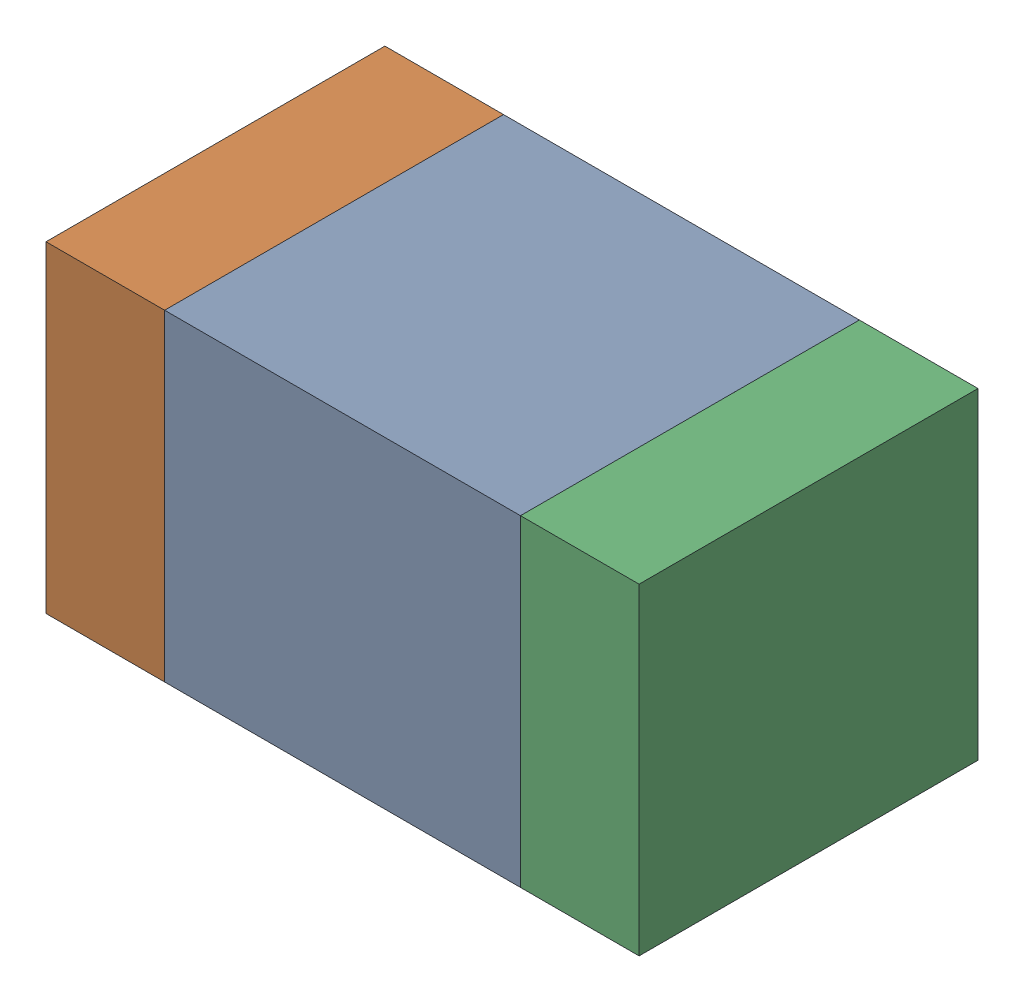
SolidWorks assembly C123_1PCB, configuration Default. Lengths in mm.
Overall size (1.75 0.95 1).
6 component instances, 2 part files, 0 mates.
Components (placement in the parent):
- 761616112-1: 761616112 [Default] at (106.6 123.2 0) size (1.05 0.95 1)
  - Extruded_14-1: Extruded_14 [Default] at origin size (1.05 0.95 1)
- 761616248-1: 761616248 [Default] at (105.9 123.2 0) size (0.35 0.95 1)
  - Extruded_15-1: Extruded_15 [Default] at origin size (0.35 0.95 1)
- 761616248-2: 761616248 [Default] at (107.3 123.2 0) size (0.35 0.95 1)
  - Extruded_15-1: Extruded_15 [Default] at origin size (0.35 0.95 1)
